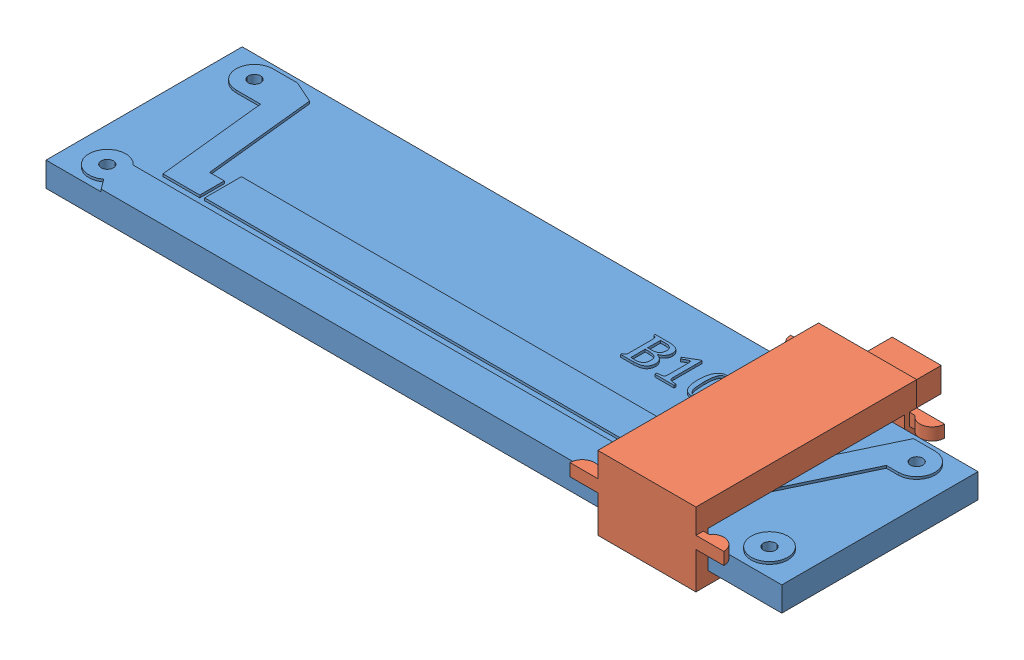
SolidWorks assembly potentionmeter, configuration 默认. Lengths in mm.
Overall size (30 3 11).
2 component instances, 2 part files, 3 mates.
Components (placement in the parent):
- potentionmeter_body-1: potentionmeter_body [默认] at (-2.027 -3.965 0) size (30 1.1 8)
- potentionmeter_slider-1: potentionmeter_slider [默认] at (7.973 -2.465 0) size (6.28 3 11)
Mates (geometry in assembly coordinates):
- 重合1: coincident anti-aligned: plane of potentionmeter_body-1 through (-2.027 -3.965 0) normal (0 -1 0); plane of potentionmeter_slider-1 through (7.973 -3.965 0) normal (0 1 0)
- 重合3: coincident anti-aligned: plane of potentionmeter_body-1 through (-17.027 -2.965 4) normal (0 0 1); plane of potentionmeter_slider-1 through (7.973 -2.465 4) normal (0 0 -1)
- LimitDistance1: limit distance = 23 mm aligned: plane of potentionmeter_body-1 through (-17.027 -2.965 -4) normal (-1 0 0); plane of potentionmeter_slider-1 through (5.973 -1.465 -4) normal (-1 0 0)
